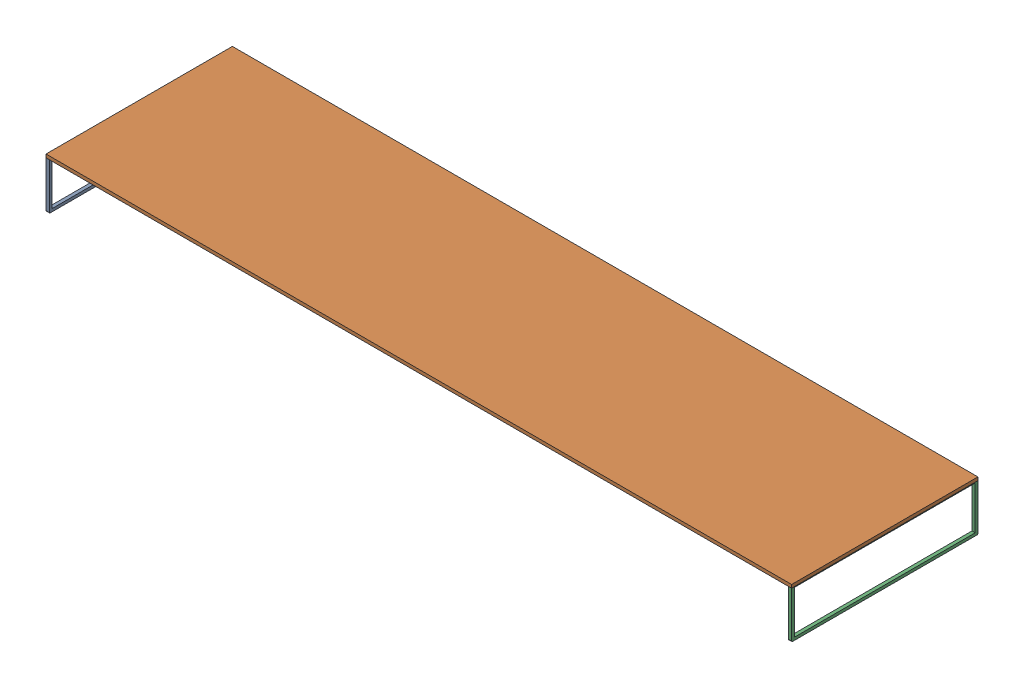
SolidWorks assembly Assembled long table, configuration Default. Lengths in mm.
Overall size (8000 535 2000).
3 component instances, 2 part files, 6 mates.
Components (placement in the parent):
- dup_icate table leg-1: dup_icate table leg [Default] at (-275.6644 1277.3757 -142.1465) size (35 500 2000)
- Top of long table-1: Top of long table [Default] at (3724.3356 363.9125 -256.4724) size (8000 35 2000)
- dup_icate table leg-2: dup_icate table leg [Default] at (7689.3356 1277.3757 -142.1465) size (35 500 2000)
Mates (geometry in assembly coordinates):
- Coincident1: coincident: plane of Top of long table-1 through (3724.3356 363.9125 -256.4724) normal (0 -1 0); plane of dup;icate table leg-2 through (8119.7325 363.9125 1558.8394) normal (0 1 0)
- Coincident2: coincident: line of Top of long table-1 through (-275.6644 363.9125 1558.8394) axis (1 0 0); line of dup;icate table leg-2 through (8119.7325 363.9125 1558.8394) axis (-1 0 0)
- Coincident8: coincident anti-aligned: plane of dup;icate table leg-1 through (-240.6644 363.9125 1558.8394) normal (0 1 0); plane of Top of long table-1 through (3724.3356 363.9125 -256.4724) normal (0 -1 0)
- Coincident9: coincident: line of dup;icate table leg-1 through (-240.6644 363.9125 1558.8394) axis (-1 0 0); plane of Top of long table-1 through (-275.6644 398.9125 1558.8394) normal (0 0 1)
- Coincident10: coincident aligned: line of dup;icate table leg-1 through (-275.6644 363.9125 1558.8394) axis (0 -1 0); line of Top of long table-1 through (-275.6644 398.9125 1558.8394) axis (0 -1 0)
- Coincident11: coincident aligned: line of Top of long table-1 through (7724.3356 398.9125 1558.8394) axis (0 -1 0); line of dup;icate table leg-2 through (7724.3356 363.9125 1558.8394) axis (0 -1 0)
